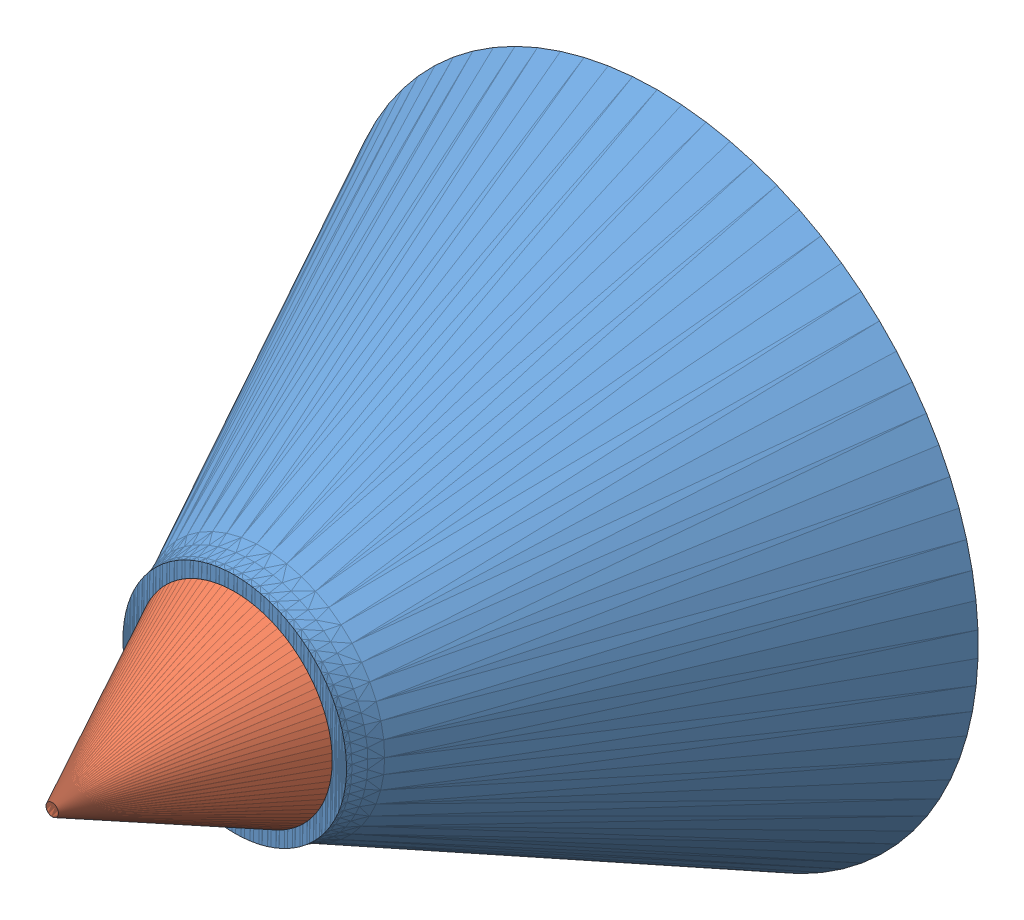
SolidWorks assembly noyau inférieur, configuration Défaut. Lengths in mm.
Overall size (25.98 26 24.57).
3 component instances, 3 part files, 0 mates.
Components (placement in the parent):
- obj6-1: obj6 [Défaut] at (0 15 0) x (1 0 0) z (0 -1 0) size (25.98 17.16 26)
- obj7-1: obj7 [Défaut] at origin (suppressed, hidden)
- obj8-1: obj8 [Défaut] at origin size (7.91 7.91 7.41)
